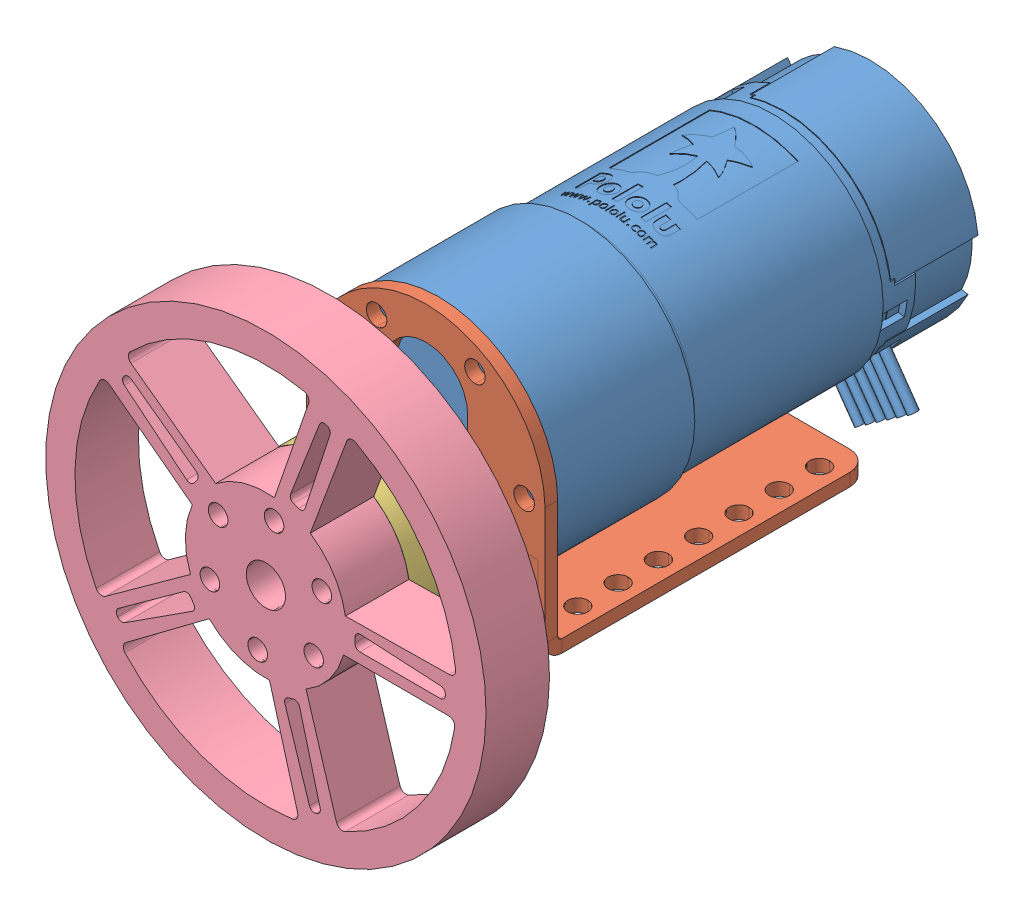
SolidWorks assembly Motor bracket hub and wheel, configuration Default. Lengths in mm.
Overall size (97.36 97.36 95.3).
4 component instances, 4 part files, 8 mates.
Components (placement in the parent):
- Motor-1: Motor [Default] at (-34.4414 -9.6533 18.8274) size (36.88 41.23 90.1)
- L bracket-1: L bracket [Default] at (-13.5164 -10.6533 32.9524) size (37.59 39.6 51.2)
- Hub-1: Hub [Default] at (-14.5163 -16.6533 53.4524) x (-0.990873 0.134796 0) z (0 0 -1) size (25.4 25.4 9.2)
- wheellayer-1: wheellayer [Default] at (-19.7583 -12.595 55.9524) x (0.612173 0.790724 0) z (0.790724 -0.612173 0) size (69.4 10 69.4)
Mates (geometry in assembly coordinates):
- Distance2: distance = 2 mm: plane of Hub-1 through (-14.5164 -16.6533 46.7524) normal (0 0 -1); plane of Motor-1 through (-14.5164 -9.6533 44.7524) normal (0 0 1)
- Concentric5: concentric: circle of Motor-1; circle of Hub-1
- Concentric17: concentric: circle of Motor-1; circle of L bracket-1
- Concentric22: concentric: cylinder of Motor-1 through (-14.5164 -9.6533 16.7524) axis (0 0 1) radius 18.4; cylinder of L bracket-1 through (-14.5164 -9.6533 40.7524) axis (0 0 1) radius 18.8
- Coincident1: coincident: plane of Motor-1 through (-14.5164 -9.6533 38.7524) normal (0 0 1); plane of L bracket-1 through (4.2796 -28.4533 38.7524) normal (0 0 -1)
- Concentric23: concentric: circle of Motor-1; circle of wheellayer-1
- Concentric24: concentric: circle of Hub-1; circle of wheellayer-1
- Coincident2: coincident: plane of Hub-1 through (-14.5164 -16.6533 55.9524) normal (0 0 1); plane of wheellayer-1 through (-14.5164 -16.6533 55.9524) normal (0 0 -1)
